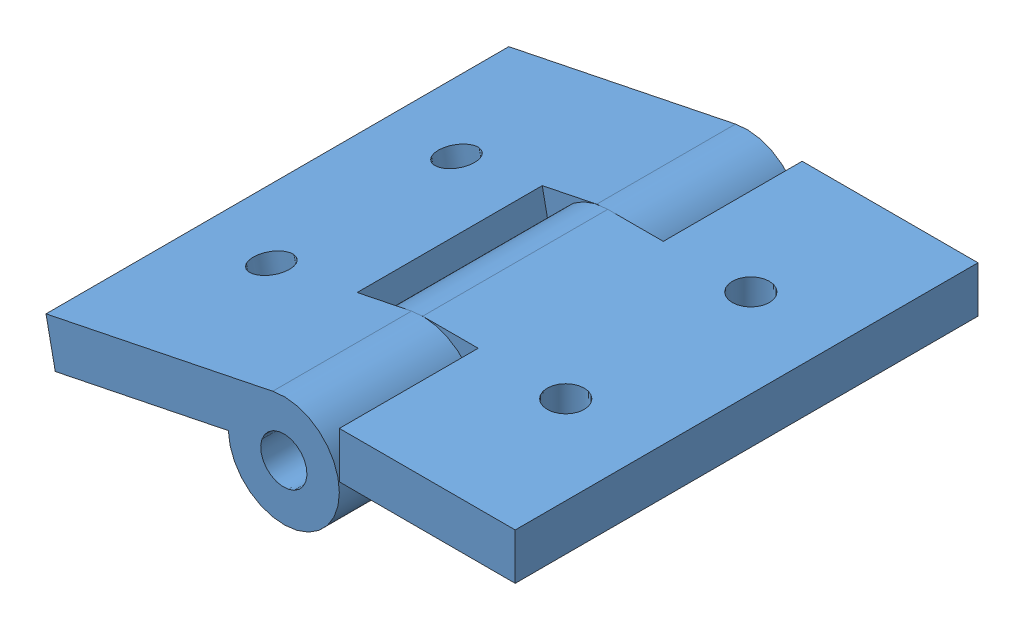
SolidWorks assembly 鉸鏈, configuration 預設. Lengths in mm.
Overall size (50.7 17.96 50).
2 component instances, 1 part files, 2 mates.
Components (placement in the parent):
- 鉸鏈-1: 鉸鏈 [左] at (0.4631 0.6018 25) size (31 12 50)
- 鉸鏈-2: 鉸鏈 [右] at (0.4631 0.6018 25) x (0.979767 0.200143 0) z (0 0 1) size (31 12 50)
Mates (geometry in assembly coordinates):
- 同軸心1: concentric aligned: cylinder of 鉸鏈-1 through (0.4631 0.6018 75) axis (0 0 -1) radius 2.5; cylinder of 鉸鏈-2 through (0.4631 0.6018 75) axis (0 0 -1) radius 2.5
- 重合/共線/共點1: coincident anti-aligned: plane of 鉸鏈-1 through (6.4631 -88.0503 60) normal (0 0 1); plane of 鉸鏈-2 through (24.0848 -85.0557 60) normal (0 0 -1)
